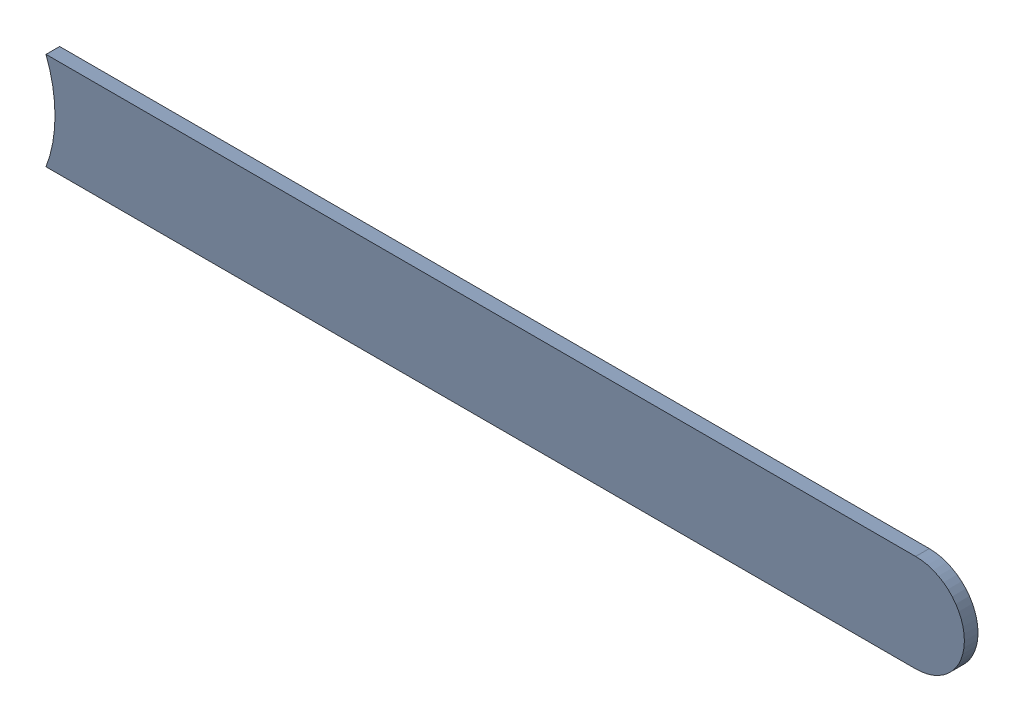
SolidWorks assembly Track (9.5mm,35.5mm)(12.1mm,35.5mm) on Bottom Layer, configuration Predeterminado. Lengths in mm.
Overall size (2.39 0.25 0.04).
2 component instances, 1 part files, 0 mates.
Components (placement in the parent):
- Track (9.5mm,35.5mm)(12.1mm,35.5mm) on Bottom Layer-1-1: Track (9.5mm,35.5mm)(12.1mm,35.5mm) on Bottom Layer-1 [Predeterminado] at (-68.317 -44.187 -0.4013) size (2.39 0.25 0.04)
  - Track (9.5mm,35.5mm)(12.1mm,35.5mm) on Bottom Layer-Part-1-1: Track (9.5mm,35.5mm)(12.1mm,35.5mm) on Bottom Layer-Part-1 [Predeterminado] at origin size (2.39 0.25 0.04)
